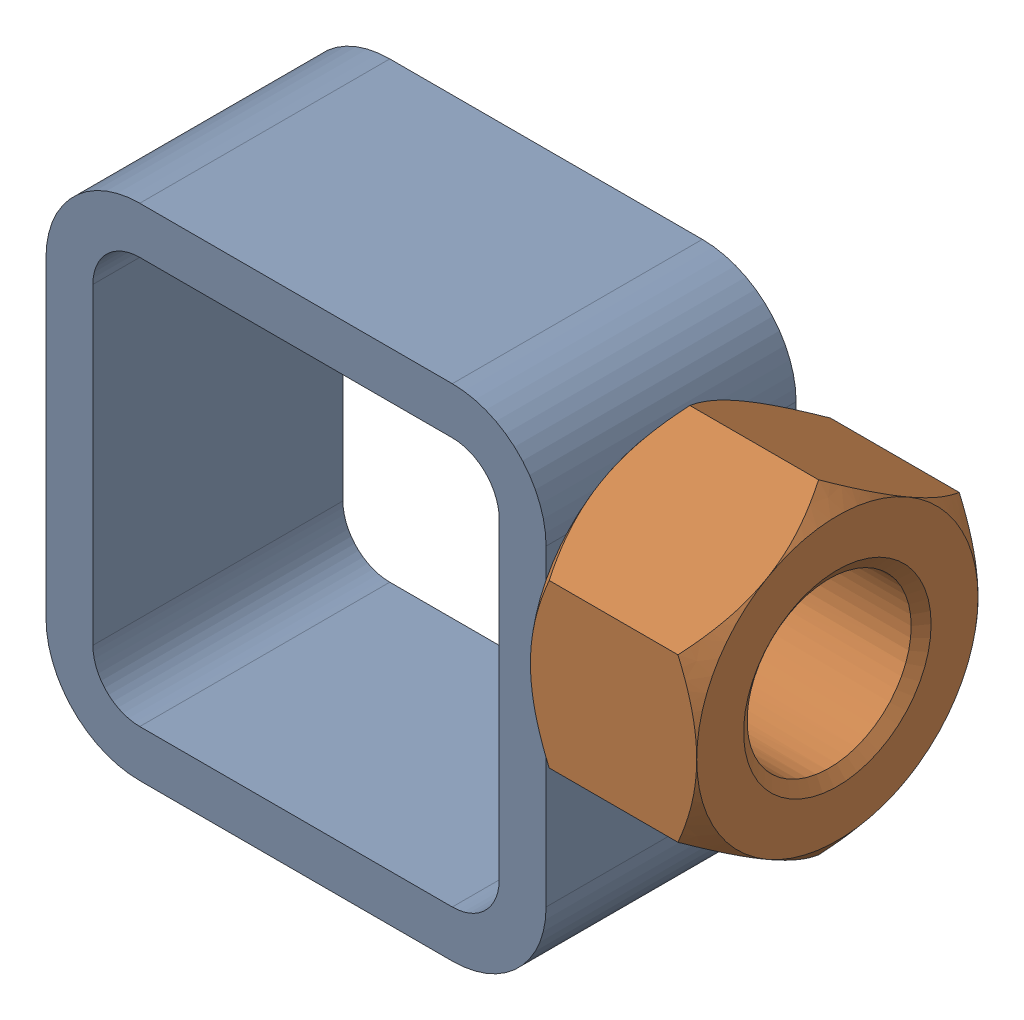
SolidWorks assembly 01-005-00-0-11, configuration Default. Lengths in mm.
Overall size (67.69 50.8 28.57).
2 component instances, 2 part files, 0 mates.
Components (placement in the parent):
- tube square_ai(PreviewCfg)-1: tube square_ai(PreviewCfg) [Default] at origin size (50.8 50.8 25.4)
- hex nut_ai(HNUT 0.7500-10-D-C)-1: hex nut_ai(HNUT 0.7500-10-D-C) [Default] at (67.691 31.75 0) x (0 0 -1) z (1 0 0) size (28.57 33 16.89)
